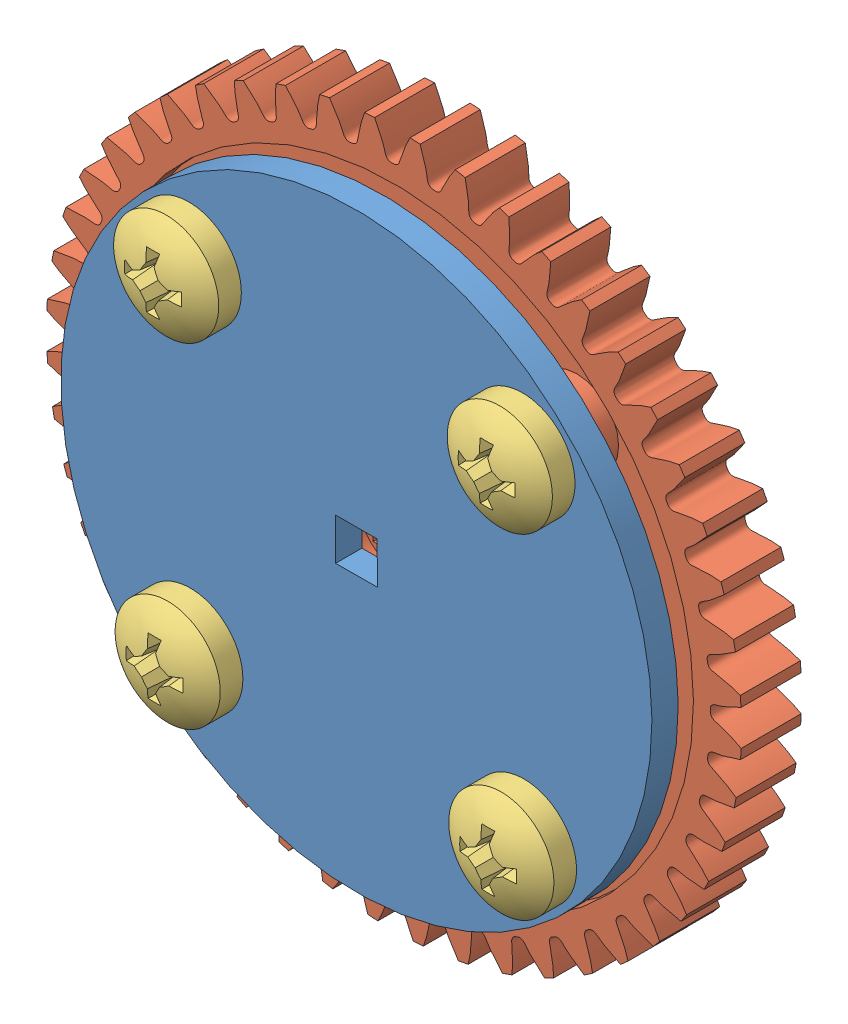
SolidWorks assembly reinforced 48T spur gear, configuration Default. Lengths in mm.
Overall size (53.41 53.41 12.53).
6 component instances, 3 part files, 9 mates.
Components (placement in the parent):
- double plate 48T gear-1: double plate 48T gear [Default] at (18.693 -8.7027 35.2657) x (0.99999 0.004571 0) z (0 0 1) size (45 45 2)
- Spur gear-1: Spur gear [48 teeth] at (18.6653 -8.727 30.0907) x (0.99999 0.004571 0) z (0 0 1) size (53.16 53.16 6.35)
- Tapping screw DIN 7049-ST4.2x9.5-C-H-S-5: Tapping screw DIN 7049-ST4.2x9.5-C-H-S [Tapping screw DIN 7049-ST4.2x9.5-C-H-S] at (31.3348 4.0552 35.2657) x (0 0 -1) z (1 0 0) size (12.53 8 8)
- Tapping screw DIN 7049-ST4.2x9.5-C-H-S-6: Tapping screw DIN 7049-ST4.2x9.5-C-H-S [Tapping screw DIN 7049-ST4.2x9.5-C-H-S] at (5.9351 3.9391 35.2657) x (0 0 -1) z (1 0 0) size (12.53 8 8)
- Tapping screw DIN 7049-ST4.2x9.5-C-H-S-7: Tapping screw DIN 7049-ST4.2x9.5-C-H-S [Tapping screw DIN 7049-ST4.2x9.5-C-H-S] at (6.0512 -21.4607 35.2657) x (0 0 -1) z (1 0 0) size (12.53 8 8)
- Tapping screw DIN 7049-ST4.2x9.5-C-H-S-8: Tapping screw DIN 7049-ST4.2x9.5-C-H-S [Tapping screw DIN 7049-ST4.2x9.5-C-H-S] at (31.4509 -21.3446 35.2657) x (0 0 -1) z (1 0 0) size (12.53 8 8)
Mates (geometry in assembly coordinates):
- Coincident2022: coincident anti-aligned: plane of double plate 48T gear-1 through (18.693 -8.7027 33.2657) normal (0 0 -1); plane of Spur gear-1 through (18.6653 -8.727 33.2657) normal (0 0 1)
- Concentric1: concentric aligned: cylinder of double plate 48T gear-1 through (31.3348 4.0552 25.2657) axis (0 0 1) radius 2.1; cylinder of Tapping screw DIN 7049-ST4.2x9.5-C-H-S-5 through (31.3348 4.0552 35.2657) axis (0 0 1) radius 2.1
- Coincident2026: coincident anti-aligned: plane of double plate 48T gear-1 through (18.693 -8.7027 35.2657) normal (0 0 1); plane of Tapping screw DIN 7049-ST4.2x9.5-C-H-S-5 through (31.3348 6.1552 35.2657) normal (0 0 -1)
- Concentric21: concentric aligned: cylinder of double plate 48T gear-1 through (5.9351 3.9391 25.2657) axis (0 0 1) radius 2.1; cylinder of Tapping screw DIN 7049-ST4.2x9.5-C-H-S-6 through (5.9351 3.9391 35.2657) axis (0 0 1) radius 2.1
- Coincident20271: coincident anti-aligned: plane of double plate 48T gear-1 through (18.693 -8.7027 35.2657) normal (0 0 1); plane of Tapping screw DIN 7049-ST4.2x9.5-C-H-S-6 through (5.9351 6.0391 35.2657) normal (0 0 -1)
- Concentric31: concentric aligned: cylinder of double plate 48T gear-1 through (6.0512 -21.4607 25.2657) axis (0 0 1) radius 2.1; cylinder of Tapping screw DIN 7049-ST4.2x9.5-C-H-S-7 through (6.0512 -21.4607 35.2657) axis (0 0 1) radius 2.1
- Coincident20281: coincident anti-aligned: plane of double plate 48T gear-1 through (18.693 -8.7027 35.2657) normal (0 0 1); plane of Tapping screw DIN 7049-ST4.2x9.5-C-H-S-7 through (6.0512 -19.3607 35.2657) normal (0 0 -1)
- Concentric41: concentric aligned: cylinder of double plate 48T gear-1 through (31.4509 -21.3446 25.2657) axis (0 0 1) radius 2.1; cylinder of Tapping screw DIN 7049-ST4.2x9.5-C-H-S-8 through (31.4509 -21.3446 35.2657) axis (0 0 1) radius 2.1
- Coincident20291: coincident anti-aligned: plane of double plate 48T gear-1 through (18.693 -8.7027 35.2657) normal (0 0 1); plane of Tapping screw DIN 7049-ST4.2x9.5-C-H-S-8 through (31.4509 -19.2446 35.2657) normal (0 0 -1)
